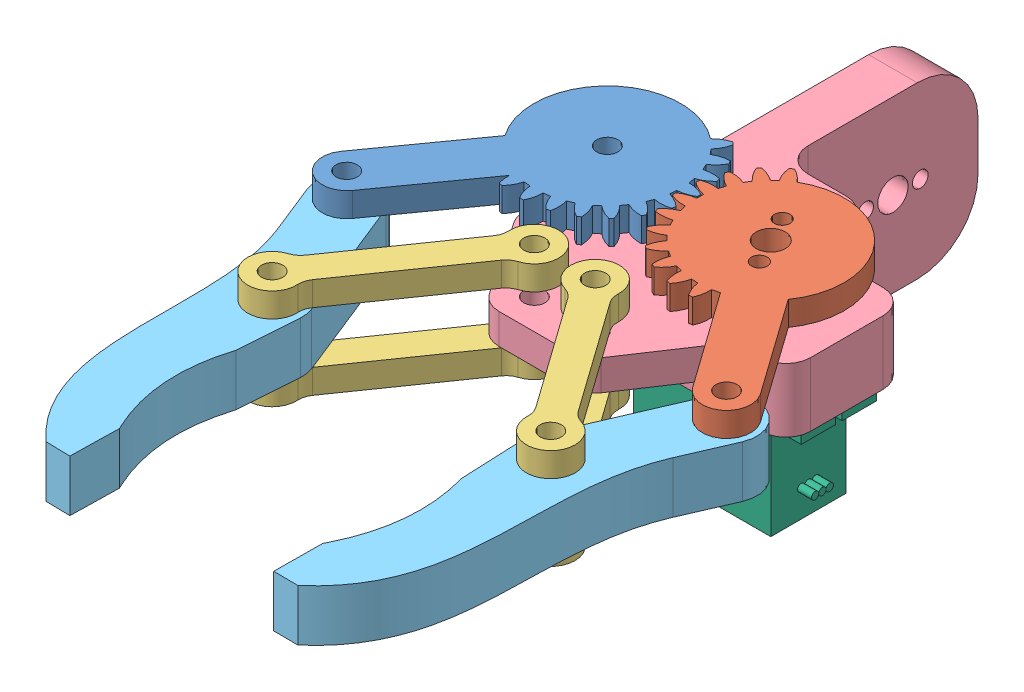
SolidWorks assembly Gripper Assembly, configuration Default. Lengths in mm.
Overall size (98.22 36.05 139.41).
10 component instances, 6 part files, 24 mates.
Components (placement in the parent):
- gear1-1: gear1 [Default] at (-22.9056 12.6028 63.2843) x (-0.581668 0 0.813426) z (-0.813426 0 -0.581668) size (49.29 4 26.63)
- gear2-1: gear2 [Default] at (5.149 12.6028 46.1292) x (-0.467421 0 -0.884035) z (0.884035 0 -0.467421) size (49.02 4 26.63)
- grip link 1-1: grip link 1 [Default] at (-26.7426 0.1028 100.5029) x (0.571471 0 -0.820623) z (0.820623 0 0.571471) size (39 4 8)
- Gripper base-1: Gripper base [Default] at (-22.027 4.1028 80.0636) size (44.4 28 77)
- grip link 1-2: grip link 1 [Default] at (18.9346 0.1028 100.3298) x (-0.579406 0 -0.815039) z (0.815039 0 -0.579406) size (39 4 8)
- Gripper 1-1: Gripper 1 [Default] at (25.0683 4.1028 73.5645) x (0 1 0) z (0.39713 0 -0.917762) size (8.5 22.22 65.31)
- Gripper 1-2: Gripper 1 [Default] at (-32.1279 12.6028 73.5771) x (0 -1 0) z (-0.371396 0 -0.928475) size (8.5 22.22 65.31)
- Servo Motor Micro  9g-1: Servo Motor Micro  9g [Default] at (4.773 -19.4472 55.0636) x (-1 0 0) z (0 0 -1) size (32.6 29.9 12.4)
- grip link 1-3: grip link 1 [Default] at (18.9346 12.6028 100.3298) x (-0.579406 0 -0.815039) z (0.815039 0 -0.579406) size (39 4 8)
- grip link 1-4: grip link 1 [Default] at (-26.7426 16.6028 100.5029) x (0.571471 0 -0.820623) z (-0.820623 0 -0.571471) size (39 4 8)
Mates (geometry in assembly coordinates):
- Concentric1: concentric aligned: cylinder of gear1-1 through (-17.027 16.6028 55.0636) axis (0 -1 0) radius 1.75; cylinder of Gripper base-1 through (-17.027 9.1028 55.0636) axis (0 -1 0) radius 1.75
- Concentric2: concentric anti-aligned: cylinder of Gripper base-1 through (9.873 4.1028 55.0636) axis (0 -1 0) radius 5.4; cylinder of gear2-1 through (9.873 12.6018 55.0636) axis (0 1 0) radius 2.4
- Coincident1: coincident aligned: plane of gear1-1 through (-34.9133 16.6028 80.0764) normal (0 1 0); plane of gear2-1 through (-4.5002 16.6028 27.8795) normal (0 1 0)
- Concentric4: concentric aligned: cylinder of grip link 1-1 through (-9.027 4.1028 75.0636) axis (0 -1 0) radius 1.75; cylinder of Gripper base-1 through (-9.027 9.1028 75.0636) axis (0 -1 0) radius 1.75
- Concentric51: concentric aligned: cylinder of Gripper base-1 through (0.973 9.1028 75.0636) axis (0 -1 0) radius 1.75; cylinder of grip link 1-2 through (0.973 4.1028 75.0636) axis (0 -1 0) radius 1.75
- Concentric6: concentric anti-aligned: cylinder of gear2-1 through (27.6714 12.6028 80.139) axis (0 1 0) radius 1.75; cylinder of Gripper 1-1 through (27.6714 12.6028 80.139) axis (0 -1 0) radius 1.75
- Concentric7: concentric aligned: cylinder of grip link 1-2 through (18.9346 4.1028 100.3298) axis (0 -1 0) radius 1.75; cylinder of Gripper 1-1 through (18.9346 12.6028 100.3298) axis (0 -1 0) radius 1.75
- Concentric8: concentric anti-aligned: cylinder of gear1-1 through (-34.9133 16.6028 80.0764) axis (0 -1 0) radius 1.75; cylinder of Gripper 1-2 through (-34.9133 4.1028 80.0764) axis (0 1 0) radius 1.75
- Concentric9: concentric anti-aligned: cylinder of grip link 1-1 through (-26.7426 4.1028 100.5029) axis (0 -1 0) radius 1.75; cylinder of Gripper 1-2 through (-26.7426 4.1028 100.5029) axis (0 1 0) radius 1.75
- Coincident2: coincident anti-aligned: plane of Gripper base-1 through (-22.027 4.1028 80.0636) normal (0 -1 0); plane of grip link 1-2 through (18.9346 4.1028 100.3298) normal (0 1 0)
- Coincident3: coincident anti-aligned: plane of grip link 1-1 through (-26.7426 4.1028 100.5029) normal (0 1 0); plane of Gripper base-1 through (-22.027 4.1028 80.0636) normal (0 -1 0)
- Coincident4: coincident anti-aligned: plane of gear2-1 through (-4.5002 12.6028 27.8795) normal (0 -1 0); plane of Gripper 1-1 through (25.0683 12.6028 73.5645) normal (0 1 0)
- Coincident5: coincident anti-aligned: plane of gear1-1 through (-34.9133 12.6028 80.0764) normal (0 -1 0); plane of Gripper 1-2 through (-32.1279 12.6028 73.5771) normal (0 1 0)
- Distance1: distance = 3.5 mm anti-aligned: plane of Gripper base-1 through (-22.027 9.1028 80.0636) normal (0 1 0); plane of gear2-1 through (-4.5002 12.6028 27.8795) normal (0 -1 0)
- GearMate1: gear = 3 : 3 mm: circle of gear1-1; cylinder of gear2-1 through (9.873 12.6018 55.0636) axis (0 1 0) radius 2.4
- Concentric10: concentric aligned: cylinder of Gripper base-1 through (9.873 4.1028 55.0636) axis (0 -1 0) radius 5.4; cylinder of Servo Motor Micro  9g-1 through (9.873 10.4528 55.0636) axis (0 -1 0) radius 2.5
- Concentric11: concentric aligned: cylinder of Gripper 1-1 through (18.9346 12.6028 100.3298) axis (0 -1 0) radius 1.75; cylinder of grip link 1-3 through (18.9346 16.6028 100.3298) axis (0 -1 0) radius 1.75
- Coincident8: coincident anti-aligned: plane of Gripper 1-1 through (25.0683 12.6028 73.5645) normal (0 1 0); plane of grip link 1-3 through (18.9346 12.6028 100.3298) normal (0 -1 0)
- Concentric12: concentric aligned: cylinder of Gripper base-1 through (0.973 9.1028 75.0636) axis (0 -1 0) radius 1.75; cylinder of grip link 1-3 through (0.973 16.6028 75.0636) axis (0 -1 0) radius 1.75
- Concentric131: concentric aligned: cylinder of Gripper 1-2 through (-26.7426 4.1028 100.5029) axis (0 1 0) radius 1.75; cylinder of grip link 1-4 through (-26.7426 12.6028 100.5029) axis (0 1 0) radius 1.75
- Concentric14: concentric anti-aligned: cylinder of Gripper base-1 through (-9.027 9.1028 75.0636) axis (0 -1 0) radius 1.75; cylinder of grip link 1-4 through (-9.027 12.6028 75.0636) axis (0 1 0) radius 1.75
- Coincident9: coincident aligned: plane of grip link 1-3 through (18.9346 16.6028 100.3298) normal (0 1 0); plane of grip link 1-4 through (-26.7426 16.6028 100.5029) normal (0 1 0)
- Coincident10: coincident anti-aligned: plane of Gripper base-1 through (-22.027 -1.3972 80.0636) normal (0 -1 0); plane of Servo Motor Micro  9g-1 through (-11.527 -1.3972 48.8636) normal (0 1 0)
- Parallel1: parallel aligned: plane of Gripper base-1 through (-12.627 -1.3972 80.0636) normal (-1 0 0); plane of Servo Motor Micro  9g-1 through (-11.527 -19.4472 55.0636) normal (-1 0 0)
